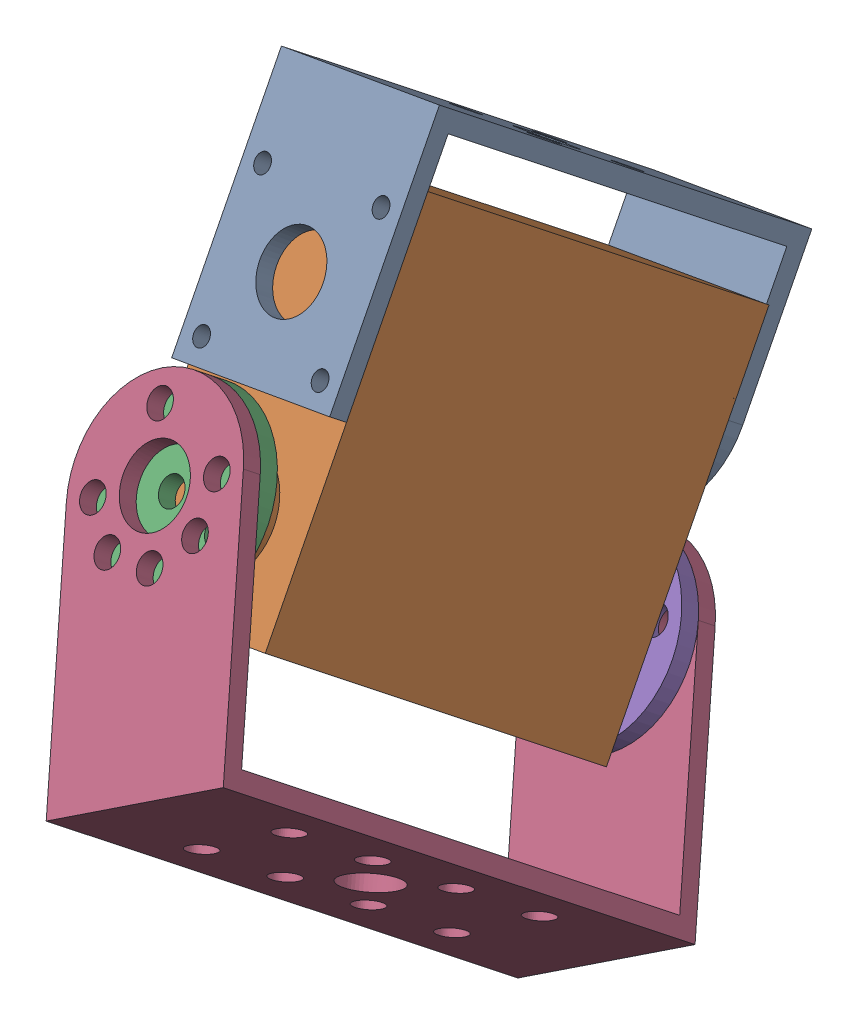
SolidWorks assembly double-shafts_servo, configuration 默认. Lengths in mm.
Overall size (45.91 82.33 80.89).
5 component instances, 5 part files, 8 mates.
Components (placement in the parent):
- 双轴窄U支架-1: 双轴窄U支架 [默认] at (-80.3378 83.8089 -40.1759) x (-0.182389 0.584413 0.790693) z (0.973252 0.221567 0.060736) size (44.2 27 20)
- 3115舵机-1: 3115舵机 [默认] at (-92.7585 87.8756 -20.626) x (0.139696 -0.780621 0.609192) z (0.973252 0.221567 0.060736) size (40 49.5 20)
- 实轴舵盘-1: 实轴舵盘 [默认] at (-80.0066 70.3932 3.4576) x (-0.976478 -0.013604 -0.215189) z (-0.115003 -0.811342 0.573147) size (20 4.5 20)
- 双轴宽U支架-1: 双轴宽U支架 [默认] at (-65.1164 16.6066 -21.6477) x (-0.182389 0.584413 0.790693) z (-0.846471 -0.502462 0.176121) size (56 37 20)
- 虚轴舵盘-1: 虚轴舵盘 [默认] at (-70.5224 40.0038 -37.6585) x (-0.500221 0.637176 -0.586332) z (0.846471 0.502462 -0.176121) size (20 3 20)
Mates (geometry in assembly coordinates):
- 重合1: coincident anti-aligned: plane of 3115舵机-1 through (-79.6418 69.2244 1.8762) normal (-0.182389 0.584413 0.790693); plane of 实轴舵盘-1 through (-79.6418 69.2244 1.8762) normal (0.182389 -0.584413 -0.790693)
- 同心1: concentric anti-aligned: circle of 3115舵机-1; circle of 实轴舵盘-1
- 同心2: concentric anti-aligned: circle of 3115舵机-1; circle of 虚轴舵盘-1
- 重合2: coincident anti-aligned: plane of 3115舵机-1 through (-71.0695 41.757 -35.2864) normal (0.182389 -0.584413 -0.790693); plane of 虚轴舵盘-1 through (-71.0695 41.757 -35.2864) normal (-0.182389 0.584413 0.790693)
- 重合5: coincident aligned: circle of 双轴窄U支架-1; circle of 3115舵机-1
- 重合6: coincident aligned: circle of 双轴窄U支架-1; circle of 3115舵机-1
- 重合8: coincident aligned: circle of 双轴宽U支架-1; circle of 虚轴舵盘-1
- 重合9: coincident aligned: circle of 双轴宽U支架-1; circle of 虚轴舵盘-1
